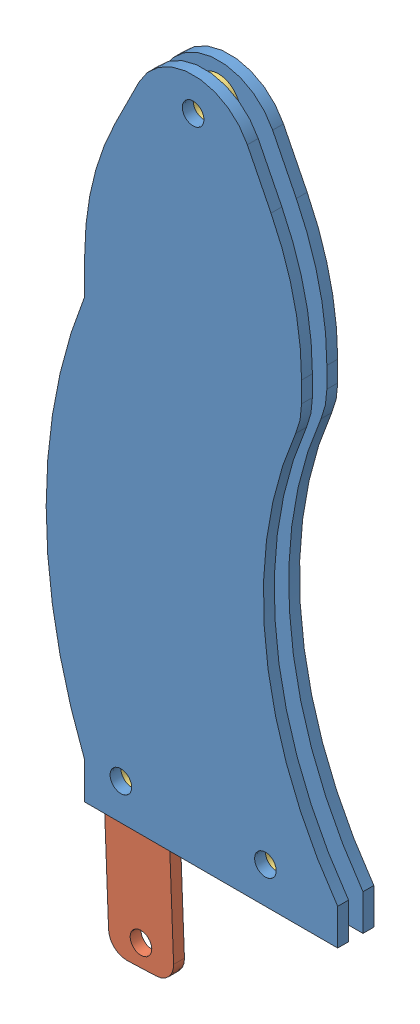
SolidWorks assembly 梳齿装配体, configuration 默认. Lengths in mm.
Overall size (84.83 226 10).
6 component instances, 3 part files, 13 mates.
Components (placement in the parent):
- 定刀片-1: 定刀片 [默认] at (-59.5194 -102.0986 187.7705) size (80.67 189.27 3)
- 定刀片-2: 定刀片 [默认] at (-59.5194 -102.0986 180.7705) size (80.67 189.27 3)
- 动刀片-1: 动刀片 [默认] at (-58.5126 -92.4494 183.7705) x (0.99924 0.038978 0) z (0 0 1) size (65.62 180 3)
- 垫圈-1: 垫圈 [默认] at (-49.5194 -92.0986 183.7705) size (12 12 4)
- 垫圈-2: 垫圈 [默认] at (-9.5194 -92.0986 187.7705) x (0.923728 0.383049 0) z (0 0 -1) size (12 12 4)
- 垫圈-3: 垫圈 [默认] at (-29.5194 77.9014 187.7705) x (0.923728 0.383049 0) z (0 0 -1) size (12 12 4)
Mates (geometry in assembly coordinates):
- 同心11: concentric anti-aligned: cylinder of 定刀片-2 through (-9.5194 -92.0986 183.7705) axis (0 0 -1) radius 3; cylinder of 垫圈-2 through (-9.5194 -92.0986 183.7705) axis (0 0 1) radius 6
- 重合11: coincident anti-aligned: plane of 定刀片-2 through (-79.5194 29.0159 183.7705) normal (0 0 1); plane of 垫圈-2 through (-9.5194 -92.0986 183.7705) normal (0 0 -1)
- 同心2: concentric anti-aligned: cylinder of 定刀片-2 through (-29.5194 77.9014 183.7705) axis (0 0 -1) radius 3; cylinder of 垫圈-3 through (-29.5194 77.9014 183.7705) axis (0 0 1) radius 3
- 重合2: coincident anti-aligned: plane of 定刀片-2 through (-79.5194 29.0159 183.7705) normal (0 0 1); circle of 垫圈-3
- 同心3: concentric aligned: cylinder of 定刀片-2 through (-49.5194 -92.0986 183.7705) axis (0 0 -1) radius 3; cylinder of 垫圈-1 through (-49.5194 -92.0986 187.7705) axis (0 0 -1) radius 3
- 重合3: coincident anti-aligned: plane of 定刀片-2 through (-79.5194 29.0159 183.7705) normal (0 0 1); plane of 垫圈-1 through (-49.5194 -92.0986 183.7705) normal (0 0 -1)
- 同心4: concentric aligned: cylinder of 动刀片-1 through (-49.5194 -92.0986 186.7705) axis (0 0 -1) radius 6; cylinder of 垫圈-1 through (-49.5194 -92.0986 187.7705) axis (0 0 -1) radius 6
- 重合4: coincident anti-aligned: plane of 定刀片-2 through (-79.5194 29.0159 183.7705) normal (0 0 1); plane of 动刀片-1 through (24.0969 -45.5381 183.7705) normal (0 0 -1)
- 同心5: concentric aligned: cylinder of 定刀片-1 through (-49.5194 -92.0986 190.7705) axis (0 0 -1) radius 3; cylinder of 垫圈-1 through (-49.5194 -92.0986 187.7705) axis (0 0 -1) radius 3
- 重合5: coincident anti-aligned: plane of 定刀片-1 through (-79.5194 29.0159 187.7705) normal (0 0 -1); plane of 垫圈-1 through (-49.5194 -92.0986 187.7705) normal (0 0 1)
- 同心6: concentric anti-aligned: cylinder of 定刀片-1 through (-9.5194 -92.0986 190.7705) axis (0 0 -1) radius 3; cylinder of 垫圈-2 through (-9.5194 -92.0986 183.7705) axis (0 0 1) radius 3
- 同心7: concentric anti-aligned: cylinder of 定刀片-2 through (-9.5194 -92.0986 183.7705) axis (0 0 -1) radius 3; cylinder of 垫圈-2 through (-9.5194 -92.0986 183.7705) axis (0 0 1) radius 3
- 同心8: concentric anti-aligned: cylinder of 定刀片-2 through (-29.5194 77.9014 183.7705) axis (0 0 -1) radius 3; cylinder of 垫圈-3 through (-29.5194 77.9014 183.7705) axis (0 0 1) radius 3
